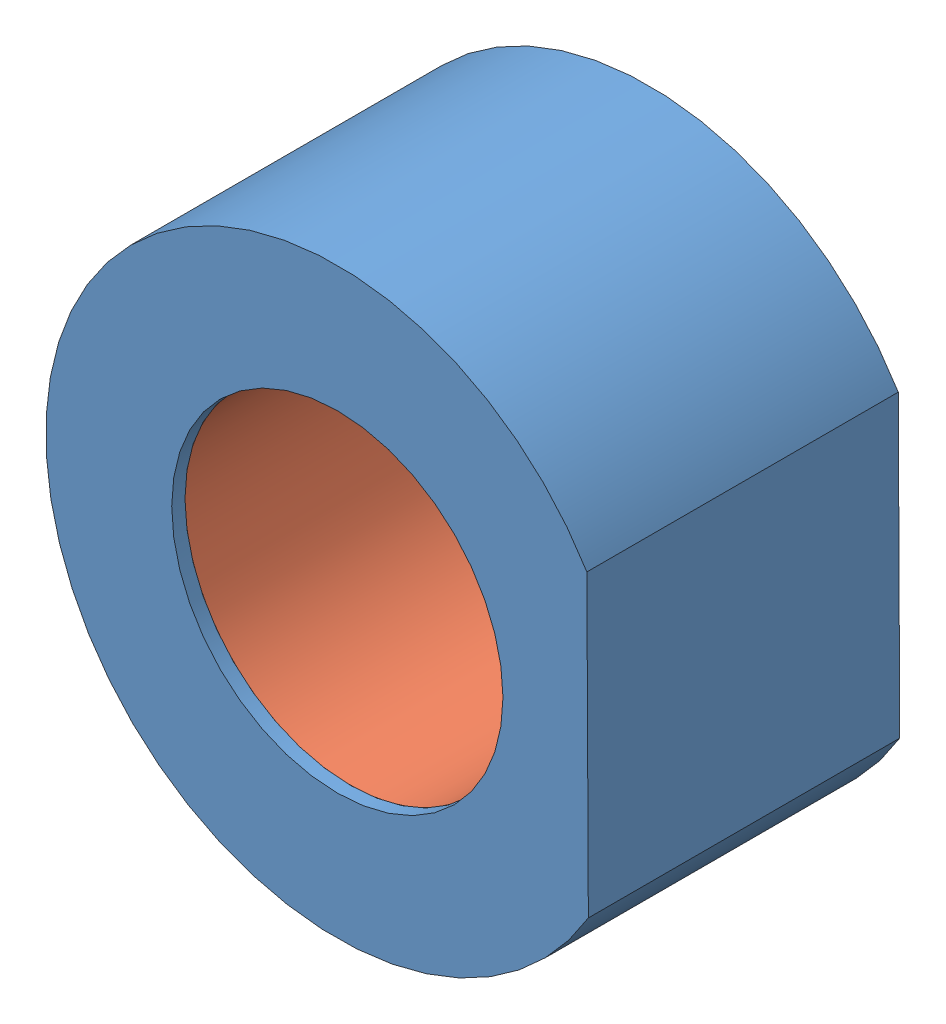
SolidWorks assembly Втулка сборка ИГ.17.01.00.20 СБ, configuration По умолчанию. Lengths in mm.
Overall size (42.37 44 23.5).
3 component instances, 3 part files, 3 mates.
Components (placement in the parent):
- Цилиндр втулки ИГ.17.01.00.21-1: Цилиндр втулки ИГ.17.01.00.21 [По умолчанию] at (1.0217 1.9724 -13) size (40.94 44 23.5)
- Обойма втулки  ИГ.17.01.00.22-2: Обойма втулки  ИГ.17.01.00.22 [По умолчанию] at (1.0217 1.9724 -13) size (32 32 22.5)
- Крышка втулки ИГ.17.01.00.23-1: Крышка втулки ИГ.17.01.00.23 [По умолчанию] at (1.0217 1.9724 -9) x (0.481382 -0.876511 0) z (0 0 -1) size (30 30 4)
Mates (geometry in assembly coordinates):
- Совпадение2: coincident aligned: circle of Обойма втулки  ИГ.17.01.00.22-2; circle of Цилиндр втулки ИГ.17.01.00.21-1
- Совпадение3: coincident anti-aligned: plane of Обойма втулки  ИГ.17.01.00.22-2 through (1.0217 1.9724 -9) normal (0 0 -1); plane of Крышка втулки ИГ.17.01.00.23-1 through (1.0217 1.9724 -9) normal (0 0 1)
- Концентричный1: concentric anti-aligned: circle of Крышка втулки ИГ.17.01.00.23-1; circle of Обойма втулки  ИГ.17.01.00.22-2
